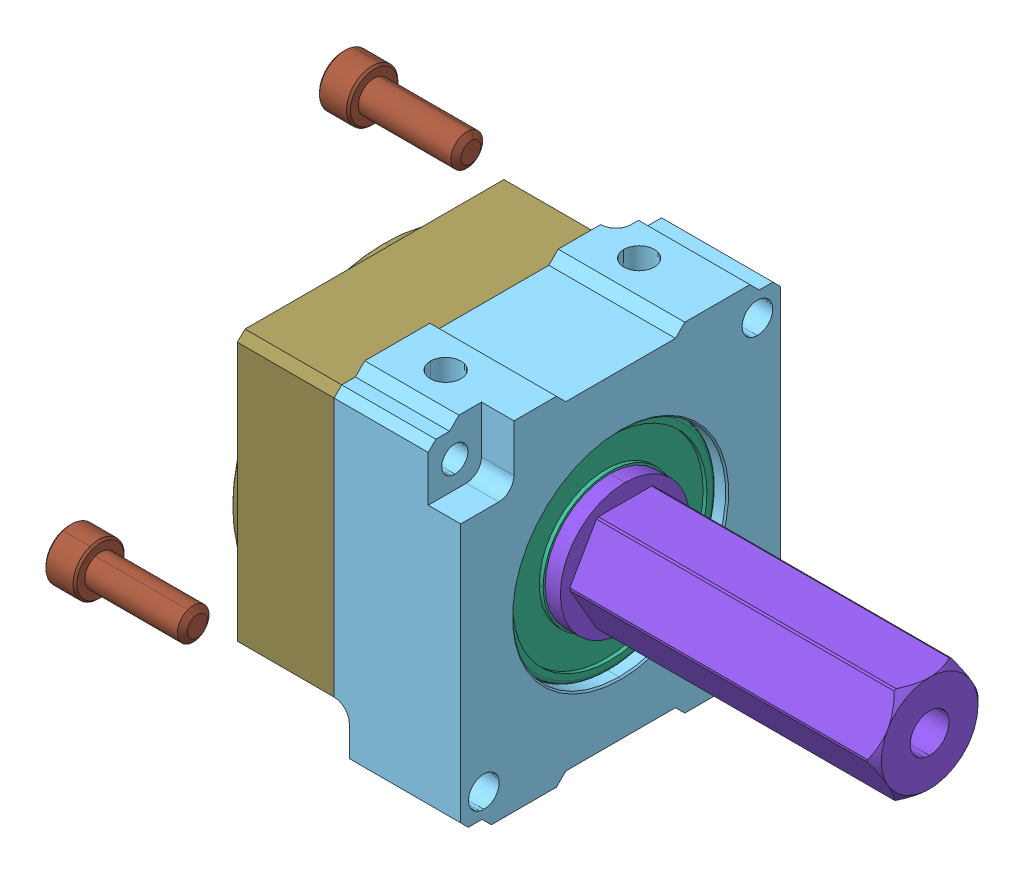
SolidWorks assembly VersaPlanetary_v2_Single_Stage_10_1_with_RS_550 (2), configuration Default. Lengths in mm.
Overall size (94.97 49.04 49.3).
21 component instances, 12 part files, 0 mates.
Components (placement in the parent):
- VersaPlanetary_v2_Single_Stage_10_1_with_RS_550 (2)^VersaPlanetary_v2_Single_Stage_10_1_with_RS_550 (2)-1: VersaPlanetary_v2_Single_Stage_10_1_with_RS_550 (2)^VersaPlanetary_v2_Single_Stage_10_1_with_RS_550 (2) [Default] at origin size (94.97 49.04 49.3) (virtual)
  - 217-2820 Rev1_Public^VersaPlanetary_v2_Single_Stage_10_1_with_RS_550 (2)_VersaPlanetary_v2_Single_Stage_10_1_with_RS_550 (2)-1: 217-2820 Rev1_Public^VersaPlanetary_v2_Single_Stage_10_1_with_RS_550 (2)_VersaPlanetary_v2_Single_Stage_10_1_with_RS_550 (2) [Default] at (-4.6546 22.225 0) x (0 -0.456494 0.889726) z (-1 0 0) size (39.22 38.88 17.4) (virtual)
    - 217-2625-100^217-2820 Rev1_Public_VersaPlanetary_v2_Single_Stage_10_1_with_RS_550 (2)_VersaPlanetary_v2_Single_Stage_10_1_with_RS_550 (2)-1: 217-2625-100^217-2820 Rev1_Public_VersaPlanetary_v2_Single_Stage_10_1_with_RS_550 (2)_VersaPlanetary_v2_Single_Stage_10_1_with_RS_550 (2) [Default] at origin size (39.22 38.88 12.7) (virtual)
      - 217-2625-008 Rev1^217-2625-100_217-2820 Rev1_Public_VersaPlanetary_v2_Single_Stage_10_1_with_RS_550 (2)_VersaPlanetary_v2_Single_Stage_10_1_with_RS_550 (2)-1: 217-2625-008 Rev1^217-2625-100_217-2820 Rev1_Public_VersaPlanetary_v2_Single_Stage_10_1_with_RS_550 (2)_VersaPlanetary_v2_Single_Stage_10_1_with_RS_550 (2) [Default] at origin size (34.7 34.7 4.7) (virtual)
      - 217-2625-010 Rev1^217-2625-100_217-2820 Rev1_Public_VersaPlanetary_v2_Single_Stage_10_1_with_RS_550 (2)_VersaPlanetary_v2_Single_Stage_10_1_with_RS_550 (2)-1: 217-2625-010 Rev1^217-2625-100_217-2820 Rev1_Public_VersaPlanetary_v2_Single_Stage_10_1_with_RS_550 (2)_VersaPlanetary_v2_Single_Stage_10_1_with_RS_550 (2) [Default] at (0 10.193 3.65) x (0.999813 0.019336 0) z (0 0 1) size (4 4 12) (virtual)
      - 217-2625-010 Rev1^217-2625-100_217-2820 Rev1_Public_VersaPlanetary_v2_Single_Stage_10_1_with_RS_550 (2)_VersaPlanetary_v2_Single_Stage_10_1_with_RS_550 (2)-2: 217-2625-010 Rev1^217-2625-100_217-2820 Rev1_Public_VersaPlanetary_v2_Single_Stage_10_1_with_RS_550 (2)_VersaPlanetary_v2_Single_Stage_10_1_with_RS_550 (2) [Default] at (8.691 -5.3258 3.65) size (4 4 12) (virtual)
      - 217-2625-010 Rev1^217-2625-100_217-2820 Rev1_Public_VersaPlanetary_v2_Single_Stage_10_1_with_RS_550 (2)_VersaPlanetary_v2_Single_Stage_10_1_with_RS_550 (2)-3: 217-2625-010 Rev1^217-2625-100_217-2820 Rev1_Public_VersaPlanetary_v2_Single_Stage_10_1_with_RS_550 (2)_VersaPlanetary_v2_Single_Stage_10_1_with_RS_550 (2) [Default] at (-8.691 -5.3258 3.65) size (4 4 12) (virtual)
      - 217-2625-005 Rev1_Planet_Revolving_Follower01^217-2625-100_217-2820 Rev1_Public_VersaPlanetary_v2_Single_Stage_10_1_with_RS_550 (2)_VersaPlanetary_v2_Single_Stage_10_1_with_RS_550 (2)-1: 217-2625-005 Rev1_Planet_Revolving_Follower01^217-2625-100_217-2820 Rev1_Public_VersaPlanetary_v2_Single_Stage_10_1_with_RS_550 (2)_VersaPlanetary_v2_Single_Stage_10_1_with_RS_550 (2) [Default] at (8.691 -5.3258 6.35) x (0.932816 0.360354 0) z (0 0 1) size (16.89 16.89 8) (virtual)
      - 217-2625-005 Rev1_Planet_Revolving_Follower01^217-2625-100_217-2820 Rev1_Public_VersaPlanetary_v2_Single_Stage_10_1_with_RS_550 (2)_VersaPlanetary_v2_Single_Stage_10_1_with_RS_550 (2)-2: 217-2625-005 Rev1_Planet_Revolving_Follower01^217-2625-100_217-2820 Rev1_Public_VersaPlanetary_v2_Single_Stage_10_1_with_RS_550 (2)_VersaPlanetary_v2_Single_Stage_10_1_with_RS_550 (2) [Default] at (-8.691 -5.3258 6.35) x (-0.932788 -0.360426 0) z (0 0 1) size (16.89 16.89 8) (virtual)
      - 217-2625-005 Rev1_Planet_Revolving_Follower01^217-2625-100_217-2820 Rev1_Public_VersaPlanetary_v2_Single_Stage_10_1_with_RS_550 (2)_VersaPlanetary_v2_Single_Stage_10_1_with_RS_550 (2)-3: 217-2625-005 Rev1_Planet_Revolving_Follower01^217-2625-100_217-2820 Rev1_Public_VersaPlanetary_v2_Single_Stage_10_1_with_RS_550 (2)_VersaPlanetary_v2_Single_Stage_10_1_with_RS_550 (2) [Default] at (0 10.193 6.35) x (0.893583 0.448898 0) z (0 0 1) size (16.89 16.89 8) (virtual)
    - 217-2625-007 Rev1_Public^217-2820 Rev1_Public_VersaPlanetary_v2_Single_Stage_10_1_with_RS_550 (2)_VersaPlanetary_v2_Single_Stage_10_1_with_RS_550 (2)-1: 217-2625-007 Rev1_Public^217-2820 Rev1_Public_VersaPlanetary_v2_Single_Stage_10_1_with_RS_550 (2)_VersaPlanetary_v2_Single_Stage_10_1_with_RS_550 (2) [Default] at (0 0 6.7) x (0.992772 0.120019 0) z (0 0 1) size (15.27 15.27 12.7) (virtual)
  - 217-2625-026 Rev1^VersaPlanetary_v2_Single_Stage_10_1_with_RS_550 (2)_VersaPlanetary_v2_Single_Stage_10_1_with_RS_550 (2)-1: 217-2625-026 Rev1^VersaPlanetary_v2_Single_Stage_10_1_with_RS_550 (2)_VersaPlanetary_v2_Single_Stage_10_1_with_RS_550 (2) [Default] at (-6.5 22.225 0) x (0 -1 0) z (-1 0 0) size (44.45 42 18.12) (virtual)
  - 217-2742-001 Rev4^VersaPlanetary_v2_Single_Stage_10_1_with_RS_550 (2)_VersaPlanetary_v2_Single_Stage_10_1_with_RS_550 (2)-1: 217-2742-001 Rev4^VersaPlanetary_v2_Single_Stage_10_1_with_RS_550 (2)_VersaPlanetary_v2_Single_Stage_10_1_with_RS_550 (2) [Default] at (0.2002 22.225 0) x (1 0 0) z (0 -0.092627 0.995701) size (7 28 28) (virtual)
  - 217-2742-001 Rev4^VersaPlanetary_v2_Single_Stage_10_1_with_RS_550 (2)_VersaPlanetary_v2_Single_Stage_10_1_with_RS_550 (2)-2: 217-2742-001 Rev4^VersaPlanetary_v2_Single_Stage_10_1_with_RS_550 (2)_VersaPlanetary_v2_Single_Stage_10_1_with_RS_550 (2) [Default] at (8.2002 22.225 0) size (7 28 28) (virtual)
  - 217-2625-017 Rev1_9714K61^VersaPlanetary_v2_Single_Stage_10_1_with_RS_550 (2)_VersaPlanetary_v2_Single_Stage_10_1_with_RS_550 (2)-1: 217-2625-017 Rev1_9714K61^VersaPlanetary_v2_Single_Stage_10_1_with_RS_550 (2)_VersaPlanetary_v2_Single_Stage_10_1_with_RS_550 (2) [Default] at (7.42 22.3002 -0.342) x (0 0.56703 0.823697) z (0 -0.823697 0.56703) size (28.51 4.98 27.43) (virtual)
  - 217-2625-003 Rev1^VersaPlanetary_v2_Single_Stage_10_1_with_RS_550 (2)_VersaPlanetary_v2_Single_Stage_10_1_with_RS_550 (2)-1: 217-2625-003 Rev1^VersaPlanetary_v2_Single_Stage_10_1_with_RS_550 (2)_VersaPlanetary_v2_Single_Stage_10_1_with_RS_550 (2) [Default] at (7.4478 22.225 0) x (0 -1 0) z (1 0 0) size (17 17 64.11) (virtual)
  - 217-2625-018 Rev1_98541A410^VersaPlanetary_v2_Single_Stage_10_1_with_RS_550 (2)_VersaPlanetary_v2_Single_Stage_10_1_with_RS_550 (2)-1: 217-2625-018 Rev1_98541A410^VersaPlanetary_v2_Single_Stage_10_1_with_RS_550 (2)_VersaPlanetary_v2_Single_Stage_10_1_with_RS_550 (2) [Default] at (-0.7046 22.225 0) x (1 0 0) z (0 -0.017452 0.999848) size (1 19.6 17.4) (virtual)
  - 832-1750-Ring-Gear-Screw_SSA0832-0500ZC^VersaPlanetary_v2_Single_Stage_10_1_with_RS_550 (2)_VersaPlanetary_v2_Single_Stage_10_1_with_RS_550 (2)-1: 832-1750-Ring-Gear-Screw_SSA0832-0500ZC^VersaPlanetary_v2_Single_Stage_10_1_with_RS_550 (2)_VersaPlanetary_v2_Single_Stage_10_1_with_RS_550 (2) [Default] at (-30.7 4.725 -17.5) x (0 0.997447 0.071411) z (0 -0.071411 0.997447) size (6.73 48.51 6.73) (virtual)
  - 217-4649-002 Rev1_SSA0832-0500ZC^VersaPlanetary_v2_Single_Stage_10_1_with_RS_550 (2)_VersaPlanetary_v2_Single_Stage_10_1_with_RS_550 (2)-1: 217-4649-002 Rev1_SSA0832-0500ZC^VersaPlanetary_v2_Single_Stage_10_1_with_RS_550 (2)_VersaPlanetary_v2_Single_Stage_10_1_with_RS_550 (2) [Default] at (-33.7 4.2645 17.9605) x (0 0.33842 -0.940995) z (0 0.940995 0.33842) size (6.73 16.76 6.73) (virtual)
  - 217-4649-002 Rev1_SSA0832-0500ZC^VersaPlanetary_v2_Single_Stage_10_1_with_RS_550 (2)_VersaPlanetary_v2_Single_Stage_10_1_with_RS_550 (2)-2: 217-4649-002 Rev1_SSA0832-0500ZC^VersaPlanetary_v2_Single_Stage_10_1_with_RS_550 (2)_VersaPlanetary_v2_Single_Stage_10_1_with_RS_550 (2) [Default] at (-33.7 40.1855 -17.9605) x (0 -0.308932 -0.951084) z (0 0.951084 -0.308932) size (6.73 16.76 6.73) (virtual)
  - 217-2816-001 Rev1^VersaPlanetary_v2_Single_Stage_10_1_with_RS_550 (2)_VersaPlanetary_v2_Single_Stage_10_1_with_RS_550 (2)-1: 217-2816-001 Rev1^VersaPlanetary_v2_Single_Stage_10_1_with_RS_550 (2)_VersaPlanetary_v2_Single_Stage_10_1_with_RS_550 (2) [Default] at (-6.35 22.225 0) x (0 -1 0) z (1 0 0) size (42 42 14.51) (virtual)
